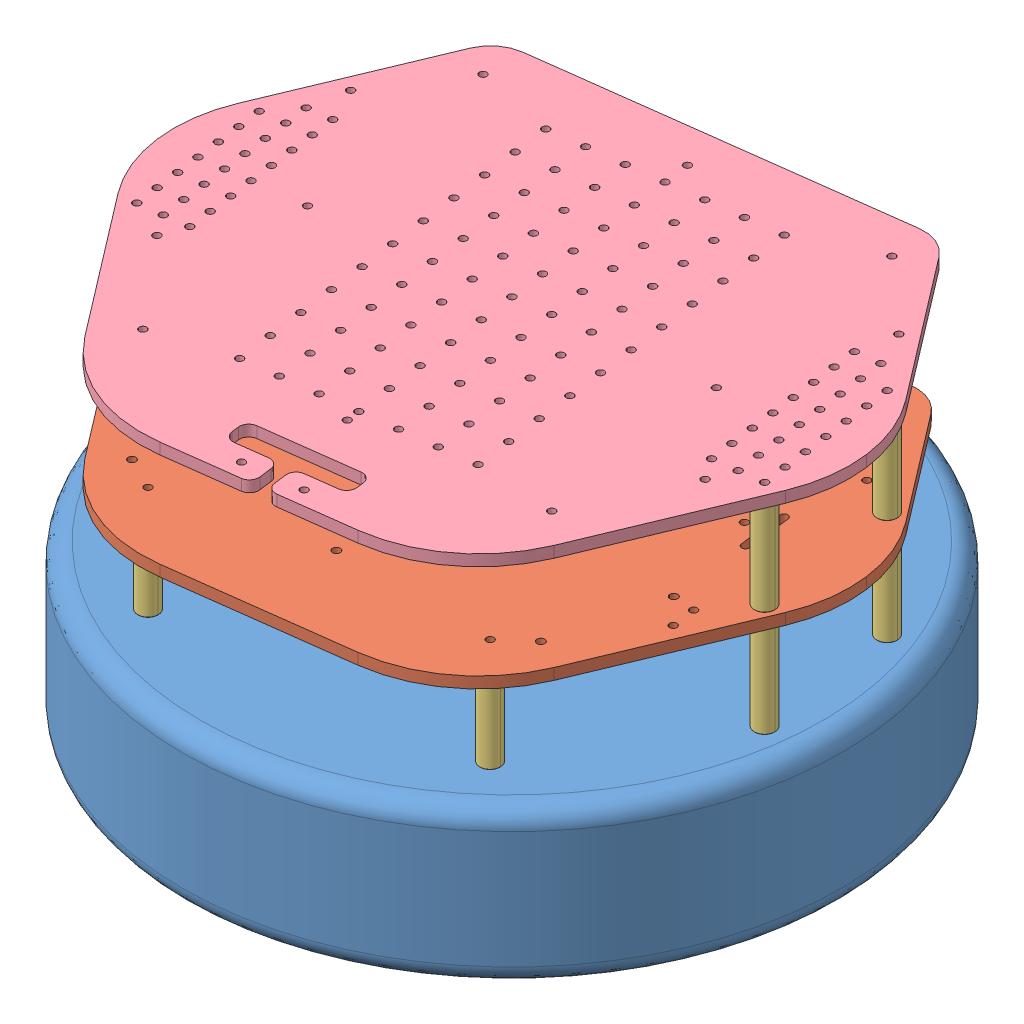
SolidWorks assembly Assem_turtleBase, configuration Default. Lengths in mm.
Overall size (374.1 211.6 354.82).
14 component instances, 5 part files, 40 mates.
Components (placement in the parent):
- kobuki-1: kobuki [Default] at (141.6159 120.0161 280.4618) size (354 98 354)
- plate_bottom.stp-1: plate_bottom.stp [Default] at (141.6159 253.8161 280.4618) x (0.991706 0 -0.128523) z (0.128523 0 0.991706) size (340 6 267.27)
- pole_middle.stp-2: pole_middle.stp [Default] at (-2.7391 249.8161 337.5886) size (11 60.8 11)
- pole_middle.stp-3: pole_middle.stp [Default] at (-12.5326 249.8161 262.0205) size (11 60.8 11)
- pole_middle.stp-4: pole_middle.stp [Default] at (295.7645 249.8161 298.903) size (11 60.8 11)
- pole_middle.stp-6: pole_middle.stp [Default] at (285.971 249.8161 223.335) size (11 60.8 11)
- pole_middle.stp-7: pole_middle.stp [Default] at (-12.5326 193.0161 262.0205) size (11 60.8 11)
- pole_middle.stp-8: pole_middle.stp [Default] at (238.3587 193.0161 388.9276) size (11 60.8 11)
- pole_middle.stp-9: pole_middle.stp [Default] at (75.7188 193.0161 410.0055) size (11 60.8 11)
- pole_middle.stp-10: pole_middle.stp [Default] at (295.7645 193.0161 298.903) size (11 60.8 11)
- pole_middle.stp-11: pole_middle.stp [Default] at (285.971 193.0161 223.335) size (11 60.8 11)
- pole_middle.stp-12: pole_middle.stp [Default] at (-2.7391 193.0161 337.5886) size (11 60.8 11)
- plate_top.stp-1: plate_top.stp [Default] at (141.6159 316.6161 280.4618) x (0.991706 0 -0.128523) z (-0.128523 0 -0.991706) size (340 6 287.27)
- TopPlate_turtle_drawing-1: TopPlate_turtle_drawing [Default] at (358.6986 316.6161 124.5682) x (-0.990342 0 0.138649) z (0 1 0) size (320.73 267.4 0) (hidden)
Mates (geometry in assembly coordinates):
- Concentric1: concentric aligned: cylinder of plate_bottom.stp-1 through (75.7188 259.8161 410.0055) axis (0 1 0) radius 2; circle of pole_bottom.stp-1
- Coincident1: coincident anti-aligned: plane of plate_bottom.stp-1 through (141.6159 253.8161 280.4618) normal (0 -1 0); plane of pole_bottom.stp-1 through (59.6159 248.2161 400.4618) normal (0 1 0)
- Concentric9: concentric aligned: cylinder of plate_bottom.stp-1 through (238.3587 259.8161 388.9276) axis (0 1 0) radius 2; cylinder of pole_middle.stp-5 through (340.907 612.7615 255.4984) axis (0 1 0) radius 1.7
- Concentric12: concentric anti-aligned: cylinder of plate_bottom.stp-1 through (295.7645 259.8161 298.903) axis (0 -1 0) radius 2; cylinder of pole_middle.stp-4 through (295.7645 249.8161 298.903) axis (0 1 0) radius 1.7
- Concentric13: concentric anti-aligned: cylinder of plate_bottom.stp-1 through (285.971 259.8161 223.335) axis (0 -1 0) radius 2; cylinder of pole_middle.stp-6 through (285.971 249.8161 223.335) axis (0 1 0) radius 1.7
- Concentric15: concentric aligned: cylinder of plate_bottom.stp-1 through (-2.7391 259.8161 337.5886) axis (0 1 0) radius 2; cylinder of pole_middle.stp-2 through (-2.7391 249.8161 337.5886) axis (0 1 0) radius 1.7
- Concentric16: concentric aligned: cylinder of plate_bottom.stp-1 through (-12.5326 259.8161 262.0205) axis (0 1 0) radius 2; cylinder of pole_middle.stp-3 through (-12.5326 249.8161 262.0205) axis (0 1 0) radius 1.7
- Coincident7: coincident anti-aligned: plane of plate_bottom.stp-1 through (141.6159 259.8161 280.4618) normal (0 1 0); plane of pole_middle.stp-3 through (-12.5326 259.8161 262.0205) normal (0 -1 0)
- Coincident8: coincident anti-aligned: plane of plate_bottom.stp-1 through (141.6159 259.8161 280.4618) normal (0 1 0); plane of pole_middle.stp-2 through (-2.7391 259.8161 337.5886) normal (0 -1 0)
- Concentric17: concentric aligned: cylinder of plate_bottom.stp-1 through (75.7188 259.8161 410.0055) axis (0 1 0) radius 2; cylinder of pole_middle.stp-1 through (176.907 612.7615 255.4984) axis (0 1 0) radius 1.7
- Coincident10: coincident anti-aligned: plane of plate_bottom.stp-1 through (141.6159 259.8161 280.4618) normal (0 1 0); plane of pole_middle.stp-1 through (176.907 622.7615 255.4984) normal (0 -1 0)
- Coincident11: coincident anti-aligned: plane of plate_bottom.stp-1 through (141.6159 259.8161 280.4618) normal (0 1 0); plane of pole_middle.stp-5 through (340.907 622.7615 255.4984) normal (0 -1 0)
- Coincident12: coincident anti-aligned: plane of plate_bottom.stp-1 through (141.6159 259.8161 280.4618) normal (0 1 0); plane of pole_middle.stp-4 through (295.7645 259.8161 298.903) normal (0 -1 0)
- Coincident13: coincident anti-aligned: plane of plate_bottom.stp-1 through (141.6159 259.8161 280.4618) normal (0 1 0); plane of pole_middle.stp-6 through (285.971 259.8161 223.335) normal (0 -1 0)
- Concentric19: concentric anti-aligned: cylinder of pole_middle.stp-4 through (295.7645 310.6161 298.903) axis (0 1 0) radius 1.7; cylinder of plate_middle.stp-2 through (295.7615 316.6161 298.9282) axis (0 -1 0) radius 2
- Concentric20: concentric anti-aligned: cylinder of pole_middle.stp-6 through (285.971 310.6161 223.335) axis (0 1 0) radius 1.7; cylinder of plate_middle.stp-2 through (285.9803 316.6161 223.3585) axis (0 -1 0) radius 2
- Coincident14: coincident anti-aligned: plane of pole_middle.stp-3 through (-12.5326 310.6161 262.0205) normal (0 1 0); plane of plate_middle.stp-2 through (141.6159 310.6161 280.4618) normal (0 -1 0)
- Concentric21: concentric anti-aligned: cylinder of kobuki-1 through (141.6159 203.0161 280.4618) axis (0 -1 0) radius 177; cylinder of plate_middle.stp-2 through (141.6159 316.6161 280.4618) axis (0 1 0) radius 2
- Concentric22: concentric aligned: cylinder of pole_middle.stp-3 through (-12.5326 249.8161 262.0205) axis (0 1 0) radius 1.7; cylinder of pole_middle.stp-7 through (-12.5326 253.8161 262.0205) axis (0 1 0) radius 1.7
- Concentric23: concentric aligned: cylinder of pole_middle.stp-2 through (-2.7391 249.8161 337.5886) axis (0 1 0) radius 1.7; cylinder of pole_middle.stp-12 through (-2.7391 253.8161 337.5886) axis (0 1 0) radius 1.7
- Concentric24: concentric aligned: cylinder of pole_middle.stp-6 through (285.971 249.8161 223.335) axis (0 1 0) radius 1.7; cylinder of pole_middle.stp-11 through (285.971 253.8161 223.335) axis (0 1 0) radius 1.7
- Concentric25: concentric aligned: cylinder of pole_middle.stp-4 through (295.7645 249.8161 298.903) axis (0 1 0) radius 1.7; cylinder of pole_middle.stp-10 through (295.7645 253.8161 298.903) axis (0 1 0) radius 1.7
- Concentric26: concentric aligned: cylinder of plate_bottom.stp-1 through (75.7188 259.8161 410.0055) axis (0 1 0) radius 2; cylinder of pole_middle.stp-9 through (75.7188 253.8161 410.0055) axis (0 1 0) radius 1.7
- Concentric27: concentric aligned: cylinder of plate_bottom.stp-1 through (238.3587 259.8161 388.9276) axis (0 1 0) radius 2; cylinder of pole_middle.stp-8 through (238.3587 253.8161 388.9276) axis (0 1 0) radius 1.7
- Coincident15: coincident anti-aligned: plane of plate_bottom.stp-1 through (141.6159 253.8161 280.4618) normal (0 -1 0); plane of pole_middle.stp-7 through (-12.5326 253.8161 262.0205) normal (0 1 0)
- Coincident16: coincident anti-aligned: plane of plate_bottom.stp-1 through (141.6159 253.8161 280.4618) normal (0 -1 0); plane of pole_middle.stp-11 through (285.971 253.8161 223.335) normal (0 1 0)
- Coincident17: coincident anti-aligned: plane of plate_bottom.stp-1 through (141.6159 253.8161 280.4618) normal (0 -1 0); plane of pole_middle.stp-10 through (295.7645 253.8161 298.903) normal (0 1 0)
- Coincident18: coincident anti-aligned: plane of plate_bottom.stp-1 through (141.6159 253.8161 280.4618) normal (0 -1 0); plane of pole_middle.stp-9 through (75.7188 253.8161 410.0055) normal (0 1 0)
- Coincident20: coincident anti-aligned: plane of plate_bottom.stp-1 through (141.6159 253.8161 280.4618) normal (0 -1 0); plane of pole_middle.stp-12 through (-2.7391 253.8161 337.5886) normal (0 1 0)
- Coincident21: coincident anti-aligned: plane of plate_bottom.stp-1 through (141.6159 253.8161 280.4618) normal (0 -1 0); plane of pole_middle.stp-8 through (238.3587 253.8161 388.9276) normal (0 1 0)
- Coincident22: coincident anti-aligned: plane of kobuki-1 through (141.6159 203.0161 280.4618) normal (0 1 0); plane of pole_middle.stp-8 through (238.3587 203.0161 388.9276) normal (0 -1 0)
- Coincident23: coincident anti-aligned: plane of pole_middle.stp-2 through (-2.7391 310.6161 337.5886) normal (0 1 0); plane of plate_top.stp-1 through (141.6159 310.6161 280.4618) normal (0 -1 0)
- Concentric33: concentric anti-aligned: circle of pole_middle.stp-2; cylinder of plate_top.stp-1 through (-2.7391 310.6161 337.5886) axis (0 -1 0) radius 2
- Concentric34: concentric anti-aligned: cylinder of pole_middle.stp-3 through (-12.5326 310.6161 262.0205) axis (0 1 0) radius 1.7; cylinder of plate_top.stp-1 through (-12.5326 310.6161 262.0205) axis (0 -1 0) radius 2
- Concentric35: concentric aligned: cylinder of pole_middle.stp-6 through (285.971 310.6161 223.335) axis (0 1 0) radius 1.7; cylinder of plate_top.stp-1 through (285.971 310.6161 223.335) axis (0 1 0) radius 2
- Concentric36: concentric aligned: cylinder of pole_middle.stp-4 through (295.7645 310.6161 298.903) axis (0 1 0) radius 1.7; cylinder of plate_top.stp-1 through (295.7645 310.6161 298.903) axis (0 1 0) radius 2
- Concentric37: concentric aligned: cylinder of kobuki-1 through (141.6159 203.0161 280.4618) axis (0 -1 0) radius 177; cylinder of plate_top.stp-1 through (141.6159 310.6161 280.4618) axis (0 -1 0) radius 2
- Coincident25: coincident: point of plate_top.stp-1; point of TopPlate_turtle-1
- Coincident28: coincident: plane of plate_top.stp-1 through (141.6159 316.6161 280.4618) normal (0 1 0); point of TopPlate_turtle-1
- Coincident29: coincident: plane of plate_top.stp-1 through (141.6159 316.6161 280.4618) normal (0 1 0); point of TopPlate_turtle-1
